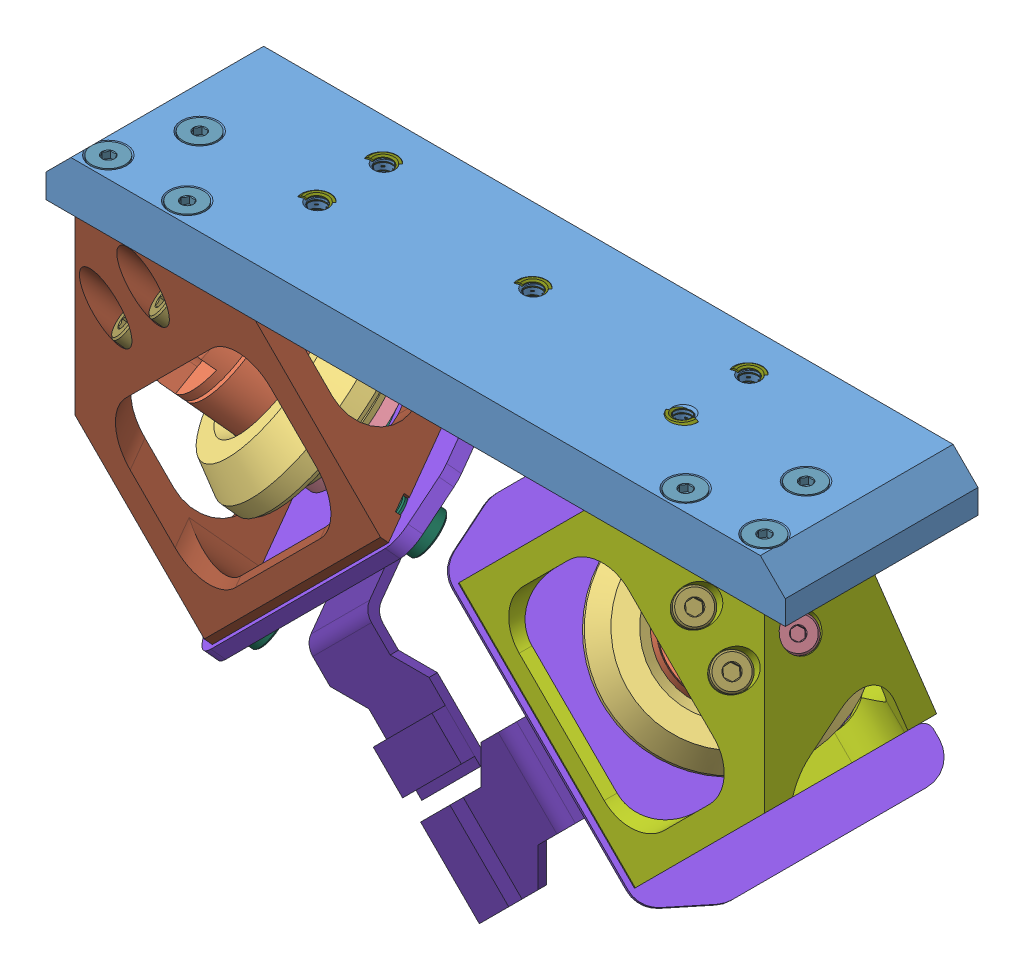
SolidWorks assembly MountingBracket, configuration Default. Lengths in mm.
Overall size (113.8 64.31 58.35).
58 component instances, 17 part files, 131 mates.
Components (placement in the parent):
- MountingBeamV2-2: MountingBeamV2 [Default] at (32.7849 42.1451 71.4667) size (89 6.09 23.2)
- ReactionWheelMotorUnit-1: ReactionWheelMotorUnit [Default] at (54.6479 30.2352 95.8648) x (-0.353553 -0.353553 0.866025) z (0.707107 -0.707107 0) size (41.14 45.44 40)
  - D1104-4000KV_rough-1: D1104-4000KV_rough [Default] at (-20.9844 2.2531 6.8074) size (14 17.5 19.2)
  - wheel-1: wheel [Default] at (-20.9844 14.7531 6.8074) x (0 0 -1) z (1 0 0) size (25 7.95 25)
  - magnetCap-1: magnetCap [Default] at (-20.9844 19.7531 6.8074) x (0 0 -1) z (-1 0 0) size (14.5 3.5 14.5)
  - magnet-1: magnet [Default] at (-20.9844 16.2531 6.8074) x (1 0 0) z (0 1 0) size (6 6 2.5)
  - sensorStandin-1: sensorStandin [Default] at (-20.9844 20.2031 6.8074) x (-1 0 0) z (0 0 -1) size (5 1.2 4.4)
  - motorBracketV2-1: motorBracketV2 [Default] at (-15.8154 -0.7969 -8.1926) x (0 0 1) z (-0.5 -0.866025 0) size (30 25.5 37.75)
  - encoderBoard-1: encoderBoard [shoulderScrews] at (-17.6931 21.4031 6.8074) x (0 0 -1) z (1 0 0) size (40 3.2 29.5)
  - 93395A137_TYPE 316 SS FLAT-HEAD SOCKET CAP SCREW-1: 93395A137_TYPE 316 SS FLAT-HEAD SOCKET CAP SCREW [93395A137] at (-20.9844 19.7531 2.0574) x (1 0 0) z (0 1 0) size (4 4 5.21)
  - 93395A137_TYPE 316 SS FLAT-HEAD SOCKET CAP SCREW-2: 93395A137_TYPE 316 SS FLAT-HEAD SOCKET CAP SCREW [93395A137] at (-20.9844 19.7531 11.5574) x (1 0 0) z (0 1 0) size (4 4 5.21)
  - 93395A138_REACTION WHEEL TYPE 316 SS FLAT-HEAD SOCKET CAP SCREW-1: 93395A138_REACTION WHEEL TYPE 316 SS FLAT-HEAD SOCKET CAP SCREW [93395A138] at (-19.2167 16.5531 8.5752) x (1 0 0) z (0 1 0) size (3.5 4 6.14)
  - 93395A138_REACTION WHEEL TYPE 316 SS FLAT-HEAD SOCKET CAP SCREW-3: 93395A138_REACTION WHEEL TYPE 316 SS FLAT-HEAD SOCKET CAP SCREW [93395A138] at (-22.7522 16.5531 8.5752) x (1 0 0) z (0 1 0) size (3.5 4 6.14)
  - 93395A138_REACTION WHEEL TYPE 316 SS FLAT-HEAD SOCKET CAP SCREW-4: 93395A138_REACTION WHEEL TYPE 316 SS FLAT-HEAD SOCKET CAP SCREW [93395A138] at (-22.7522 16.5531 5.0396) x (1 0 0) z (0 1 0) size (3.5 4 6.14)
  - 93395A138_REACTION WHEEL TYPE 316 SS FLAT-HEAD SOCKET CAP SCREW-5: 93395A138_REACTION WHEEL TYPE 316 SS FLAT-HEAD SOCKET CAP SCREW [93395A138] at (-19.2167 16.5531 5.0396) x (1 0 0) z (0 1 0) size (3.5 4 6.14)
- ReactionWheelMotorUnitReverse-1: ReactionWheelMotorUnitReverse [Default] at (-3.9163 45.0735 59.5186) x (-0.353553 0.353553 -0.866025) z (-0.707107 -0.707107 0) size (41.14 45.44 40)
  - D1104-4000KV_rough-1: D1104-4000KV_rough [Default] at (-20.9844 2.2531 6.8074) size (14 17.5 19.2)
  - wheel-1: wheel [Default] at (-20.9844 14.7531 6.8074) size (25 7.95 25)
  - magnetCap-1: magnetCap [Default] at (-20.9844 19.7531 6.8074) x (-1 0 0) z (0 0 1) size (14.5 3.5 14.5)
  - magnet-1: magnet [Default] at (-20.9844 16.2531 6.8074) x (1 0 0) z (0 1 0) size (6 6 2.5)
  - sensorStandin-1: sensorStandin [Default] at (-20.9844 20.2031 6.8074) x (0 0 -1) z (1 0 0) size (5 1.2 4.4)
  - motorBracketV2Reverse-1: motorBracketV2Reverse [Default] at (-26.1535 -0.7969 21.8074) x (0 0 -1) z (0.5 -0.866025 0) size (30 25.5 37.75)
  - encoderBoard-1: encoderBoard [shoulderScrews] at (-24.2758 21.4031 6.8074) x (0 0 1) z (-1 0 0) size (40 3.2 29.5)
  - 93395A137_TYPE 316 SS FLAT-HEAD SOCKET CAP SCREW-1: 93395A137_TYPE 316 SS FLAT-HEAD SOCKET CAP SCREW [93395A137] at (-16.2344 19.7531 6.8074) x (1 0 0) z (0 1 0) size (4 4 5.21)
  - 93395A137_TYPE 316 SS FLAT-HEAD SOCKET CAP SCREW-2: 93395A137_TYPE 316 SS FLAT-HEAD SOCKET CAP SCREW [93395A137] at (-25.7344 19.7531 6.8074) x (1 0 0) z (0 1 0) size (4 4 5.21)
  - 93395A138_REACTION WHEEL TYPE 316 SS FLAT-HEAD SOCKET CAP SCREW-1: 93395A138_REACTION WHEEL TYPE 316 SS FLAT-HEAD SOCKET CAP SCREW [93395A138] at (-22.7522 16.5531 8.5752) x (1 0 0) z (0 1 0) size (3.5 4 6.14)
  - 93395A138_REACTION WHEEL TYPE 316 SS FLAT-HEAD SOCKET CAP SCREW-2: 93395A138_REACTION WHEEL TYPE 316 SS FLAT-HEAD SOCKET CAP SCREW [93395A138] at (-19.2167 16.5531 8.5752) x (1 0 0) z (0 1 0) size (3.5 4 6.14)
  - 93395A138_REACTION WHEEL TYPE 316 SS FLAT-HEAD SOCKET CAP SCREW-3: 93395A138_REACTION WHEEL TYPE 316 SS FLAT-HEAD SOCKET CAP SCREW [93395A138] at (-19.2167 16.5531 5.0396) x (1 0 0) z (0 1 0) size (3.5 4 6.14)
  - 93395A138_REACTION WHEEL TYPE 316 SS FLAT-HEAD SOCKET CAP SCREW-4: 93395A138_REACTION WHEEL TYPE 316 SS FLAT-HEAD SOCKET CAP SCREW [93395A138] at (-22.7522 16.5531 5.0396) x (1 0 0) z (0 1 0) size (3.5 4 6.14)
- 92290A012_TYPE 316 SS SOCKET HEAD CAP SCREW-6: 92290A012_TYPE 316 SS SOCKET HEAD CAP SCREW [92290A012] at (0.4749 26.5551 78.0709) x (0.72702 0.684653 0.051888) z (0.612372 -0.612372 -0.5) size (3.8 3.8 7.44)
- 92290A012_TYPE 316 SS SOCKET HEAD CAP SCREW-9: 92290A012_TYPE 316 SS SOCKET HEAD CAP SCREW [92290A012] at (60.595 31.0551 78.0709) x (0.72702 -0.684653 -0.051888) z (-0.612372 -0.612372 -0.5) size (3.8 3.8 7.44)
- 92290A012_TYPE 316 SS SOCKET HEAD CAP SCREW-7: 92290A012_TYPE 316 SS SOCKET HEAD CAP SCREW [92290A012] at (65.095 26.5551 78.0709) x (0.72702 -0.684653 -0.051888) z (-0.612372 -0.612372 -0.5) size (3.8 3.8 7.44)
- 92290A012_TYPE 316 SS SOCKET HEAD CAP SCREW-8: 92290A012_TYPE 316 SS SOCKET HEAD CAP SCREW [92290A012] at (4.9749 31.0551 78.0709) x (0.094564 0.684653 -0.722709) z (0.612372 -0.612372 -0.5) size (3.8 3.8 7.44)
- 92855A839_18-8 SS LOW-PROFILE SCKT HEAD SCREWS-7: 92855A839_18-8 SS LOW-PROFILE SCKT HEAD SCREWS [92855A839] at (67.0388 28.4989 72.3095) x (-0.632456 0 0.774597) z (-0.612372 -0.612372 -0.5) size (3.8 3.8 9.77)
- 92855A839_18-8 SS LOW-PROFILE SCKT HEAD SCREWS-5: 92855A839_18-8 SS LOW-PROFILE SCKT HEAD SCREWS [92855A839] at (-1.4689 28.4989 72.3095) x (0.632456 0 0.774597) z (0.612372 -0.612372 -0.5) size (3.8 3.8 9.77)
- 92855A839_18-8 SS LOW-PROFILE SCKT HEAD SCREWS-4: 92855A839_18-8 SS LOW-PROFILE SCKT HEAD SCREWS [92855A839] at (62.5388 32.9989 72.3095) x (-0.047367 0.65974 -0.75) z (-0.612372 -0.612372 -0.5) size (3.8 3.8 9.77)
- 92855A839_18-8 SS LOW-PROFILE SCKT HEAD SCREWS-6: 92855A839_18-8 SS LOW-PROFILE SCKT HEAD SCREWS [92855A839] at (3.0311 32.9989 72.3095) x (0.707107 0.707107 0) z (0.612372 -0.612372 -0.5) size (3.8 3.8 9.77)
- 93395A138_TYPE 316 SS FLAT-HEAD SOCKET CAP SCREW-7: 93395A138_TYPE 316 SS FLAT-HEAD SOCKET CAP SCREW [93395A138] at (72.2849 46.1451 80.5667) x (-0.866025 0 -0.5) z (0 1 0) size (4 4 6.22)
- 93395A138_TYPE 316 SS FLAT-HEAD SOCKET CAP SCREW-6: 93395A138_TYPE 316 SS FLAT-HEAD SOCKET CAP SCREW [93395A138] at (62.7849 46.1451 80.5667) x (0.866025 0 -0.5) z (0 1 0) size (4 4 6.22)
- 93395A138_TYPE 316 SS FLAT-HEAD SOCKET CAP SCREW-5: 93395A138_TYPE 316 SS FLAT-HEAD SOCKET CAP SCREW [93395A138] at (-3.7151 46.1451 72.5667) x (0 0 -1) z (0 1 0) size (4 4 6.22)
- 93395A138_TYPE 316 SS FLAT-HEAD SOCKET CAP SCREW-4: 93395A138_TYPE 316 SS FLAT-HEAD SOCKET CAP SCREW [93395A138] at (2.7849 46.1451 80.5667) x (0 0 1) z (0 1 0) size (4 4 6.22)
- 93395A138_TYPE 316 SS FLAT-HEAD SOCKET CAP SCREW-8: 93395A138_TYPE 316 SS FLAT-HEAD SOCKET CAP SCREW [93395A138] at (69.2849 46.1451 72.5667) x (0.866025 0 -0.5) z (0 1 0) size (4 4 6.22)
- 93395A138_TYPE 316 SS FLAT-HEAD SOCKET CAP SCREW-9: 93395A138_TYPE 316 SS FLAT-HEAD SOCKET CAP SCREW [93395A138] at (-6.7151 46.1451 80.5667) x (0 0 1) z (0 1 0) size (4 4 6.22)
- 92290A012_TYPE 316 SS SOCKET HEAD CAP SCREW-13: 92290A012_TYPE 316 SS SOCKET HEAD CAP SCREW [92290A012] at (15.9156 34.7063 60.4988) x (-0.419788 -0.7878 0.45072) z (-0.612372 0.612372 0.5) size (3.8 3.8 7.44)
- 92290A012_TYPE 316 SS SOCKET HEAD CAP SCREW-12: 92290A012_TYPE 316 SS SOCKET HEAD CAP SCREW [92290A012] at (49.6542 34.7063 60.4988) x (0.771612 -0.325295 -0.546625) z (0.612372 0.612372 0.5) size (3.8 3.8 7.44)
- 92290A012_TYPE 316 SS SOCKET HEAD CAP SCREW-11: 92290A012_TYPE 316 SS SOCKET HEAD CAP SCREW [92290A012] at (68.7461 15.6144 60.4988) x (-0.742298 0.662993 0.097129) z (0.612372 0.612372 0.5) size (3.8 3.8 7.44)
- 92290A012_TYPE 316 SS SOCKET HEAD CAP SCREW-10: 92290A012_TYPE 316 SS SOCKET HEAD CAP SCREW [92290A012] at (-3.1762 15.6144 60.4988) x (0.773051 0.331426 0.540878) z (-0.612372 0.612372 0.5) size (3.8 3.8 7.44)
- M2x0.4x6mm_shoulderScrew_90278A431_18-8 STAINLESS STEEL PRECISION SHOULDER SCREW-1: M2x0.4x6mm_shoulderScrew_90278A431_18-8 STAINLESS STEEL PRECISION SHOULDER SCREW [90278A431] at (56.3278 3.196 76.9174) x (-0.615543 0.766199 -0.184515) z (-0.612372 -0.612372 -0.5) size (5 5 8.25)
- M2x0.4x6mm_shoulderScrew_90278A431_18-8 STAINLESS STEEL PRECISION SHOULDER SCREW-2: M2x0.4x6mm_shoulderScrew_90278A431_18-8 STAINLESS STEEL PRECISION SHOULDER SCREW [90278A431] at (37.2359 22.2879 76.9174) x (-0.673365 0.735396 -0.075972) z (-0.612372 -0.612372 -0.5) size (5 5 8.25)
- M2x0.4x6mm_shoulderScrew_90278A431_18-8 STAINLESS STEEL PRECISION SHOULDER SCREW-3: M2x0.4x6mm_shoulderScrew_90278A431_18-8 STAINLESS STEEL PRECISION SHOULDER SCREW [90278A431] at (9.2421 3.196 76.9174) x (-0.615543 0.027548 -0.787622) z (0.612372 -0.612372 -0.5) size (5 5 8.25)
- M2x0.4x6mm_shoulderScrew_90278A431_18-8 STAINLESS STEEL PRECISION SHOULDER SCREW-4: M2x0.4x6mm_shoulderScrew_90278A431_18-8 STAINLESS STEEL PRECISION SHOULDER SCREW [90278A431] at (28.334 22.2879 76.9174) x (-0.482367 -0.790505 0.37739) z (0.612372 -0.612372 -0.5) size (5 5 8.25)
- 91630A221_SCREW-LOCK HELICAL INSERTS WITHOUT PRONG-1: 91630A221_SCREW-LOCK HELICAL INSERTS WITHOUT PRONG [91630A221] at (54.7849 46.1451 72.8667) x (1 0 0) z (0 0 -1) size (3.78 2.46 4.27)
- 91630A221_SCREW-LOCK HELICAL INSERTS WITHOUT PRONG-2: 91630A221_SCREW-LOCK HELICAL INSERTS WITHOUT PRONG [91630A221] at (54.7849 46.1451 64.8667) x (-0.939694 0 0.342017) z (0.342017 0 0.939694) size (3.78 2.46 4.27)
- 91630A221_SCREW-LOCK HELICAL INSERTS WITHOUT PRONG-3: 91630A221_SCREW-LOCK HELICAL INSERTS WITHOUT PRONG [91630A221] at (32.7849 46.1451 68.8667) x (-0.939694 0 0.342017) z (0.342017 0 0.939694) size (3.78 2.46 4.27)
- 91630A221_SCREW-LOCK HELICAL INSERTS WITHOUT PRONG-4: 91630A221_SCREW-LOCK HELICAL INSERTS WITHOUT PRONG [91630A221] at (10.7849 46.1451 64.8667) x (-0.939694 0 0.342017) z (0.342017 0 0.939694) size (3.78 2.46 4.27)
- 91630A221_SCREW-LOCK HELICAL INSERTS WITHOUT PRONG-5: 91630A221_SCREW-LOCK HELICAL INSERTS WITHOUT PRONG [91630A221] at (10.7849 46.1451 72.8667) x (-0.939694 0 0.342017) z (0.342017 0 0.939694) size (3.78 2.46 4.27)
- encoderCable-1: encoderCable [Default] at (52.5468 2.9364 82.6661) x (-0.707107 0.707107 0) z (-0.707107 -0.707107 0) size (13.31 11.37 21.76)
- encoderCable-2: encoderCable [Default] at (28.5936 18.5069 82.6661) x (-0.707107 -0.707107 0) z (0.707107 -0.707107 0) size (13.31 11.37 21.76)
Mates (geometry in assembly coordinates):
- Concentric1: concentric aligned: cylinder of MountingBeamV2-2 through (2.7849 46.1451 80.5667) axis (0 1 0) radius 1.2; cylinder of ReactionWheelMotorUnitReverse-1/motorBracketV2Reverse-1 through (2.7849 40.2451 80.5667) axis (0 1 0) radius 0.8
- Concentric2: concentric aligned: cylinder of MountingBeamV2-2 through (-6.7151 46.1451 80.5667) axis (0 1 0) radius 1.2; cylinder of ReactionWheelMotorUnitReverse-1/motorBracketV2Reverse-1 through (-6.7151 40.2451 80.5667) axis (0 1 0) radius 0.8
- Coincident1: coincident anti-aligned: plane of MountingBeamV2-2 through (32.7849 40.2451 71.4667) normal (0 -1 0); plane of ReactionWheelMotorUnitReverse-1/motorBracketV2Reverse-1 through (12.4981 40.2451 57.0667) normal (0 1 0)
- Concentric3: concentric aligned: cylinder of MountingBeamV2-2 through (72.2849 46.1451 80.5667) axis (0 1 0) radius 1.2; cylinder of ReactionWheelMotorUnit-1/motorBracketV2-1 through (72.2849 40.2451 80.5667) axis (0 1 0) radius 0.8
- Concentric4: concentric aligned: cylinder of MountingBeamV2-2 through (62.7849 46.1451 80.5667) axis (0 1 0) radius 1.2; cylinder of ReactionWheelMotorUnit-1/motorBracketV2-1 through (62.7849 40.2451 80.5667) axis (0 1 0) radius 0.8
- Coincident2: coincident anti-aligned: plane of MountingBeamV2-2 through (32.7849 40.2451 71.4667) normal (0 -1 0); plane of ReactionWheelMotorUnit-1/motorBracketV2-1 through (74.2849 40.2451 57.0667) normal (0 1 0)
- Concentric6: concentric anti-aligned: cylinder of ReactionWheelMotorUnit-1/encoderBoard-1 through (46.5924 31.6444 57.9988) axis (-0.612372 -0.612372 -0.5) radius 1.5; cylinder of 90318A101_ULTRA-LOW-PROFILE PRECISION SHOULDER SCREW-1 through (50.4809 35.533 61.1738) axis (0.612372 0.612372 0.5) radius 1.1906
- Coincident3: coincident anti-aligned: plane of ReactionWheelMotorUnit-1/encoderBoard-1 through (51.6305 17.5906 69.0406) normal (-0.612372 -0.612372 -0.5); plane of 90318A101_ULTRA-LOW-PROFILE PRECISION SHOULDER SCREW-1 through (44.9086 33.3282 57.9988) normal (0.612372 0.612372 0.5)
- Concentric12: concentric anti-aligned: cylinder of ReactionWheelMotorUnitReverse-1/motorBracketV2Reverse-1 through (2.4081 24.622 76.4924) axis (-0.612372 0.612372 0.5) radius 2; cylinder of 92290A012_TYPE 316 SS SOCKET HEAD CAP SCREW-6 through (-3.8117 30.8417 81.5709) axis (0.612372 -0.612372 -0.5) radius 1.9
- Coincident9: coincident anti-aligned: plane of ReactionWheelMotorUnitReverse-1/motorBracketV2Reverse-1 through (-10.241 20.5578 82.2917) normal (-0.612372 0.612372 0.5); plane of 92290A012_TYPE 316 SS SOCKET HEAD CAP SCREW-6 through (-2.587 29.617 80.5709) normal (0.612372 -0.612372 -0.5)
- Concentric13: concentric anti-aligned: cylinder of ReactionWheelMotorUnitReverse-1/motorBracketV2Reverse-1 through (6.9081 29.122 76.4924) axis (-0.612372 0.612372 0.5) radius 2; cylinder of 92290A012_TYPE 316 SS SOCKET HEAD CAP SCREW-8 through (0.6883 35.3417 81.5709) axis (0.612372 -0.612372 -0.5) radius 1.9
- Coincident11: coincident anti-aligned: plane of ReactionWheelMotorUnitReverse-1/motorBracketV2Reverse-1 through (-10.241 20.5578 82.2917) normal (-0.612372 0.612372 0.5); plane of 92290A012_TYPE 316 SS SOCKET HEAD CAP SCREW-8 through (1.913 34.117 80.5709) normal (0.612372 -0.612372 -0.5)
- Concentric14: concentric anti-aligned: cylinder of ReactionWheelMotorUnit-1/motorBracketV2-1 through (58.6618 29.122 76.4924) axis (0.612372 0.612372 0.5) radius 2; cylinder of 92290A012_TYPE 316 SS SOCKET HEAD CAP SCREW-9 through (64.8816 35.3417 81.5709) axis (-0.612372 -0.612372 -0.5) radius 1.9
- Concentric15: concentric anti-aligned: cylinder of ReactionWheelMotorUnit-1/motorBracketV2-1 through (63.1618 24.622 76.4924) axis (0.612372 0.612372 0.5) radius 2; cylinder of 92290A012_TYPE 316 SS SOCKET HEAD CAP SCREW-7 through (69.3816 30.8417 81.5709) axis (-0.612372 -0.612372 -0.5) radius 1.9
- Coincident12: coincident anti-aligned: plane of ReactionWheelMotorUnit-1/motorBracketV2-1 through (54.5977 41.771 82.2917) normal (0.612372 0.612372 0.5); plane of 92290A012_TYPE 316 SS SOCKET HEAD CAP SCREW-7 through (68.1568 29.617 80.5709) normal (-0.612372 -0.612372 -0.5)
- Coincident13: coincident anti-aligned: plane of ReactionWheelMotorUnit-1/motorBracketV2-1 through (54.5977 41.771 82.2917) normal (0.612372 0.612372 0.5); plane of 92290A012_TYPE 316 SS SOCKET HEAD CAP SCREW-9 through (63.6568 34.117 80.5709) normal (-0.612372 -0.612372 -0.5)
- Coincident24: coincident aligned: cone of MountingBeamV2-2 through (62.7849 46.1451 80.5667) axis (0 -1 0); cone of 93395A138_TYPE 316 SS FLAT-HEAD SOCKET CAP SCREW-6 through (62.7849 44.9451 80.5667) axis (0 -1 0)
- Coincident25: coincident aligned: cone of MountingBeamV2-2 through (72.2849 46.1451 80.5667) axis (0 -1 0); cone of 93395A138_TYPE 316 SS FLAT-HEAD SOCKET CAP SCREW-7 through (72.2849 44.9451 80.5667) axis (0 -1 0)
- Coincident26: coincident aligned: cone of MountingBeamV2-2 through (69.2849 46.1451 72.5667) axis (0 -1 0); cone of 93395A138_TYPE 316 SS FLAT-HEAD SOCKET CAP SCREW-8 through (69.2849 44.9451 72.5667) axis (0 -1 0)
- Coincident28: coincident aligned: cone of MountingBeamV2-2 through (-6.7151 46.1451 80.5667) axis (0 -1 0); cone of 93395A138_TYPE 316 SS FLAT-HEAD SOCKET CAP SCREW-9 through (-6.7151 44.9451 80.5667) axis (0 -1 0)
- Coincident29: coincident aligned: cone of MountingBeamV2-2 through (2.7849 46.1451 80.5667) axis (0 -1 0); cone of 93395A138_TYPE 316 SS FLAT-HEAD SOCKET CAP SCREW-4 through (2.7849 44.9451 80.5667) axis (0 -1 0)
- Coincident30: coincident aligned: cone of MountingBeamV2-2 through (-3.7151 46.1451 72.5667) axis (0 -1 0); cone of 93395A138_TYPE 316 SS FLAT-HEAD SOCKET CAP SCREW-5 through (-3.7151 44.9451 72.5667) axis (0 -1 0)
- Concentric20: concentric anti-aligned: cylinder of ReactionWheelMotorUnit-1/motorBracketV2-1 through (66.664 13.5323 58.7988) axis (-0.612372 -0.612372 -0.5) radius 1; cylinder of 90318A101_ULTRA-LOW-PROFILE PRECISION SHOULDER SCREW-2 through (69.5728 16.4411 61.1738) axis (0.612372 0.612372 0.5) radius 1.1906
- Concentric21: concentric anti-aligned: cylinder of ReactionWheelMotorUnit-1/motorBracketV2-1 through (39.4404 24.4925 78.7174) axis (-0.612372 -0.612372 -0.5) radius 1; cylinder of 90318A101_ULTRA-LOW-PROFILE PRECISION SHOULDER SCREW-3 through (42.3492 27.4012 81.0924) axis (0.612372 0.612372 0.5) radius 1.1906
- Concentric22: concentric anti-aligned: circle of ReactionWheelMotorUnit-1/motorBracketV2-1; cylinder of 90318A101_ULTRA-LOW-PROFILE PRECISION SHOULDER SCREW-8 through (61.4411 8.3093 81.0924) axis (0.612372 0.612372 0.5) radius 1.1906
- Concentric23: concentric anti-aligned: cylinder of ReactionWheelMotorUnitReverse-1/motorBracketV2Reverse-1 through (17.9977 32.6242 58.7988) axis (0.612372 -0.612372 -0.5) radius 1; cylinder of 90318A101_ULTRA-LOW-PROFILE PRECISION SHOULDER SCREW-5 through (15.0889 35.533 61.1738) axis (-0.612372 0.612372 0.5) radius 1.1906
- Concentric24: concentric anti-aligned: cylinder of ReactionWheelMotorUnitReverse-1/motorBracketV2Reverse-1 through (-1.0942 13.5323 58.7988) axis (0.612372 -0.612372 -0.5) radius 1; cylinder of 90318A101_ULTRA-LOW-PROFILE PRECISION SHOULDER SCREW-4 through (-4.0029 16.4411 61.1738) axis (-0.612372 0.612372 0.5) radius 1.1906
- Concentric25: concentric anti-aligned: cylinder of ReactionWheelMotorUnitReverse-1/motorBracketV2Reverse-1 through (7.0375 5.4006 78.7174) axis (0.612372 -0.612372 -0.5) radius 1; cylinder of 90318A101_ULTRA-LOW-PROFILE PRECISION SHOULDER SCREW-6 through (4.1288 8.3093 81.0924) axis (-0.612372 0.612372 0.5) radius 1.1906
- Concentric26: concentric anti-aligned: cylinder of ReactionWheelMotorUnitReverse-1/motorBracketV2Reverse-1 through (26.1294 24.4925 78.7174) axis (0.612372 -0.612372 -0.5) radius 1; cylinder of 90318A101_ULTRA-LOW-PROFILE PRECISION SHOULDER SCREW-7 through (23.2207 27.4012 81.0924) axis (-0.612372 0.612372 0.5) radius 1.1906
- Coincident31: coincident anti-aligned: plane of ReactionWheelMotorUnitReverse-1/encoderBoard-1 through (13.9394 17.5906 69.0406) normal (0.612372 -0.612372 -0.5); plane of 90318A101_ULTRA-LOW-PROFILE PRECISION SHOULDER SCREW-4 through (0.9229 14.4317 56.9677) normal (-0.612372 0.612372 0.5)
- Coincident32: coincident anti-aligned: plane of ReactionWheelMotorUnitReverse-1/encoderBoard-1 through (13.9394 17.5906 69.0406) normal (0.612372 -0.612372 -0.5); plane of 90318A101_ULTRA-LOW-PROFILE PRECISION SHOULDER SCREW-6 through (6.3335 2.737 77.9174) normal (-0.612372 0.612372 0.5)
- Coincident33: coincident anti-aligned: plane of ReactionWheelMotorUnitReverse-1/encoderBoard-1 through (13.9394 17.5906 69.0406) normal (0.612372 -0.612372 -0.5); plane of 90318A101_ULTRA-LOW-PROFILE PRECISION SHOULDER SCREW-7 through (27.222 25.0837 76.1314) normal (-0.612372 0.612372 0.5)
- Coincident34: coincident anti-aligned: plane of ReactionWheelMotorUnitReverse-1/encoderBoard-1 through (13.9394 17.5906 69.0406) normal (0.612372 -0.612372 -0.5); plane of 90318A101_ULTRA-LOW-PROFILE PRECISION SHOULDER SCREW-5 through (20.0148 33.5236 56.9677) normal (-0.612372 0.612372 0.5)
- Coincident35: coincident anti-aligned: plane of ReactionWheelMotorUnit-1/encoderBoard-1 through (51.6305 17.5906 69.0406) normal (-0.612372 -0.612372 -0.5); plane of 90318A101_ULTRA-LOW-PROFILE PRECISION SHOULDER SCREW-3 through (38.3478 25.0837 76.1314) normal (0.612372 0.612372 0.5)
- Coincident36: coincident anti-aligned: plane of ReactionWheelMotorUnit-1/encoderBoard-1 through (51.6305 17.5906 69.0406) normal (-0.612372 -0.612372 -0.5); plane of 90318A101_ULTRA-LOW-PROFILE PRECISION SHOULDER SCREW-8 through (57.4397 5.9918 76.1314) normal (0.612372 0.612372 0.5)
- Coincident37: coincident anti-aligned: plane of ReactionWheelMotorUnit-1/encoderBoard-1 through (51.6305 17.5906 69.0406) normal (-0.612372 -0.612372 -0.5); plane of 90318A101_ULTRA-LOW-PROFILE PRECISION SHOULDER SCREW-2 through (65.5714 14.1235 56.2129) normal (0.612372 0.612372 0.5)
- Coincident38: coincident anti-aligned: plane of MountingBeamV2-2 through (32.7849 46.1451 71.4667) normal (0 1 0); plane of 91630A221_SCREW-LOCK HELICAL INSERTS WITHOUT PRONG-1 through (54.7849 46.1451 72.8667) normal (0 -1 0)
- Coincident39: coincident: line of MountingBeamV2-2 through (54.7849 40.2451 72.8667) axis (0 1 0); unknown of 91630A221_SCREW-LOCK HELICAL INSERTS WITHOUT PRONG-1
- Parallel1: parallel anti-aligned: plane of MountingBeamV2-2 through (77.2849 40.2451 83.0667) normal (0 0 1); plane of 91630A221_SCREW-LOCK HELICAL INSERTS WITHOUT PRONG-1 through (55.7914 46.1451 72.8667) normal (0 0 -1)
- Coincident41: coincident anti-aligned: plane of MountingBeamV2-2 through (32.7849 46.1451 71.4667) normal (0 1 0); plane of 91630A221_SCREW-LOCK HELICAL INSERTS WITHOUT PRONG-2 through (54.7849 46.1451 64.8667) normal (0 -1 0)
- Parallel2: parallel aligned: plane of MountingBeamV2-2 through (77.2849 40.2451 83.0667) normal (0 0 1); plane of 91630A221_SCREW-LOCK HELICAL INSERTS WITHOUT PRONG-2 through (55.7914 44.1237 64.8668) normal (0 0 1)
- Coincident43: coincident: line of MountingBeamV2-2 through (54.7849 40.2451 64.8667) axis (0 1 0); unknown of 91630A221_SCREW-LOCK HELICAL INSERTS WITHOUT PRONG-2
- Coincident46: coincident: line of MountingBeamV2-2 through (32.7849 40.2451 68.8667) axis (0 1 0); unknown of 91630A221_SCREW-LOCK HELICAL INSERTS WITHOUT PRONG-3
- Coincident47: coincident anti-aligned: plane of MountingBeamV2-2 through (32.7849 46.1451 71.4667) normal (0 1 0); plane of 91630A221_SCREW-LOCK HELICAL INSERTS WITHOUT PRONG-3 through (32.7849 46.1451 68.8667) normal (0 -1 0)
- Parallel3: parallel aligned: plane of MountingBeamV2-2 through (77.2849 40.2451 83.0667) normal (0 0 1); plane of 91630A221_SCREW-LOCK HELICAL INSERTS WITHOUT PRONG-3 through (33.7914 44.1237 68.8668) normal (0 0 1)
- Coincident51: coincident anti-aligned: plane of MountingBeamV2-2 through (32.7849 46.1451 71.4667) normal (0 1 0); plane of 91630A221_SCREW-LOCK HELICAL INSERTS WITHOUT PRONG-4 through (10.7849 46.1451 64.8667) normal (0 -1 0)
- Coincident52: coincident: line of MountingBeamV2-2 through (10.7849 40.2451 64.8667) axis (0 1 0); unknown of 91630A221_SCREW-LOCK HELICAL INSERTS WITHOUT PRONG-4
- Parallel4: parallel aligned: plane of MountingBeamV2-2 through (77.2849 40.2451 83.0667) normal (0 0 1); plane of 91630A221_SCREW-LOCK HELICAL INSERTS WITHOUT PRONG-4 through (11.7914 44.1237 64.8668) normal (0 0 1)
- Coincident54: coincident anti-aligned: plane of MountingBeamV2-2 through (32.7849 46.1451 71.4667) normal (0 1 0); plane of 91630A221_SCREW-LOCK HELICAL INSERTS WITHOUT PRONG-5 through (10.7849 46.1451 72.8667) normal (0 -1 0)
- Coincident55: coincident: line of MountingBeamV2-2 through (10.7849 40.2451 72.8667) axis (0 1 0); unknown of 91630A221_SCREW-LOCK HELICAL INSERTS WITHOUT PRONG-5
- Parallel5: parallel aligned: plane of MountingBeamV2-2 through (77.2849 40.2451 83.0667) normal (0 0 1); plane of 91630A221_SCREW-LOCK HELICAL INSERTS WITHOUT PRONG-5 through (11.7914 44.1237 72.8668) normal (0 0 1)
- Parallel6: parallel aligned: plane of MountingBeamV2-2 through (77.2849 40.2451 83.0667) normal (0 0 1); plane of 93395A138_TYPE 316 SS FLAT-HEAD SOCKET CAP SCREW-7 through (72.6602 45.3051 79.9167) normal (0 0 1)
- Parallel7: parallel aligned: plane of MountingBeamV2-2 through (77.2849 40.2451 83.0667) normal (0 0 1); plane of 93395A138_TYPE 316 SS FLAT-HEAD SOCKET CAP SCREW-6 through (63.1602 45.3051 79.9167) normal (0 0 1)
- Parallel8: parallel aligned: plane of MountingBeamV2-2 through (77.2849 40.2451 83.0667) normal (0 0 1); plane of 93395A138_TYPE 316 SS FLAT-HEAD SOCKET CAP SCREW-8 through (69.6602 45.3051 71.9167) normal (0 0 1)
- Parallel9: parallel aligned: plane of MountingBeamV2-2 through (77.2849 40.2451 83.0667) normal (0 0 1); plane of 93395A138_TYPE 316 SS FLAT-HEAD SOCKET CAP SCREW-4 through (3.1602 45.3051 79.9167) normal (0 0 1)
- Parallel10: parallel aligned: plane of MountingBeamV2-2 through (77.2849 40.2451 83.0667) normal (0 0 1); plane of 93395A138_TYPE 316 SS FLAT-HEAD SOCKET CAP SCREW-9 through (-6.3398 45.3051 79.9167) normal (0 0 1)
- Parallel11: parallel aligned: plane of MountingBeamV2-2 through (77.2849 40.2451 83.0667) normal (0 0 1); plane of 93395A138_TYPE 316 SS FLAT-HEAD SOCKET CAP SCREW-5 through (-3.3398 45.3051 71.9167) normal (0 0 1)
- Parallel12: parallel: line of ReactionWheelMotorUnitReverse-1/motorBracketV2Reverse-1 through (-8.7151 40.2451 82.5667) axis (0 -1 0); plane of 92290A012_TYPE 316 SS SOCKET HEAD CAP SCREW-6 through (-3.3918 30.4951 80.2597) normal (0.632456 0 0.774597)
- Parallel13: parallel: line of ReactionWheelMotorUnitReverse-1/motorBracketV2Reverse-1 through (-8.7151 40.2451 82.5667) axis (0 -1 0); plane of 92290A012_TYPE 316 SS SOCKET HEAD CAP SCREW-8 through (1.1082 34.9951 80.2597) normal (0.632456 0 0.774597)
- Parallel15: parallel: line of ReactionWheelMotorUnit-1/motorBracketV2-1 through (74.2849 19.0319 82.5667) axis (0 1 0); plane of 92290A012_TYPE 316 SS SOCKET HEAD CAP SCREW-9 through (63.5129 34.9951 81.4216) normal (0.632456 0 -0.774597)
- Parallel16: parallel: line of ReactionWheelMotorUnit-1/motorBracketV2-1 through (74.2849 19.0319 82.5667) axis (0 1 0); plane of 92290A012_TYPE 316 SS SOCKET HEAD CAP SCREW-7 through (69.3724 29.8105 80.5951) normal (-0.632456 0 0.774597)
- Parallel18: parallel aligned: plane of ReactionWheelMotorUnit-1/encoderBoard-1 through (60.5577 -1.7664 81.8145) normal (-0.353553 -0.353553 0.866025); plane of 90318A101_ULTRA-LOW-PROFILE PRECISION SHOULDER SCREW-8 through (57.2661 4.7824 77.0315) normal (-0.353553 -0.353553 0.866025)
- Parallel19: parallel aligned: plane of ReactionWheelMotorUnit-1/encoderBoard-1 through (60.5577 -1.7664 81.8145) normal (-0.353553 -0.353553 0.866025); plane of 90318A101_ULTRA-LOW-PROFILE PRECISION SHOULDER SCREW-2 through (65.3978 12.9142 57.1129) normal (-0.353553 -0.353553 0.866025)
- Parallel20: parallel aligned: plane of ReactionWheelMotorUnit-1/encoderBoard-1 through (60.5577 -1.7664 81.8145) normal (-0.353553 -0.353553 0.866025); plane of 90318A101_ULTRA-LOW-PROFILE PRECISION SHOULDER SCREW-3 through (38.1742 23.8743 77.0315) normal (-0.353553 -0.353553 0.866025)
- Parallel21: parallel aligned: plane of ReactionWheelMotorUnit-1/encoderBoard-1 through (60.5577 -1.7664 81.8145) normal (-0.353553 -0.353553 0.866025); plane of 90318A101_ULTRA-LOW-PROFILE PRECISION SHOULDER SCREW-1 through (46.3059 32.006 57.1129) normal (-0.353553 -0.353553 0.866025)
- Parallel22: parallel aligned: plane of ReactionWheelMotorUnitReverse-1/encoderBoard-1 through (33.2964 26.5179 81.8145) normal (0.353553 -0.353553 0.866025); plane of 90318A101_ULTRA-LOW-PROFILE PRECISION SHOULDER SCREW-6 through (7.6557 4.1343 77.0315) normal (0.353553 -0.353553 0.866025)
- Parallel23: parallel aligned: plane of ReactionWheelMotorUnitReverse-1/encoderBoard-1 through (33.2964 26.5179 81.8145) normal (0.353553 -0.353553 0.866025); plane of 90318A101_ULTRA-LOW-PROFILE PRECISION SHOULDER SCREW-7 through (26.7476 23.2262 77.0315) normal (0.353553 -0.353553 0.866025)
- Parallel24: parallel aligned: plane of ReactionWheelMotorUnitReverse-1/encoderBoard-1 through (-5.4177 8.6634 56.2667) normal (-0.707107 -0.707107 0); plane of 90318A101_ULTRA-LOW-PROFILE PRECISION SHOULDER SCREW-4 through (0.5279 13.0328 57.4035) normal (-0.707107 -0.707107 0)
- Parallel25: parallel aligned: plane of ReactionWheelMotorUnitReverse-1/encoderBoard-1 through (-5.4177 8.6634 56.2667) normal (-0.707107 -0.707107 0); plane of 90318A101_ULTRA-LOW-PROFILE PRECISION SHOULDER SCREW-5 through (19.6198 32.1246 57.4035) normal (-0.707107 -0.707107 0)
- Coincident56: coincident anti-aligned: plane of ReactionWheelMotorUnitReverse-1/motorBracketV2Reverse-1 through (-11.772 22.0888 83.5417) normal (-0.612372 0.612372 0.5); plane of 92855A839_18-8 SS LOW-PROFILE SCKT HEAD SCREWS-5 through (-6.3679 33.3979 76.3095) normal (0.612372 -0.612372 -0.5)
- Concentric27: concentric anti-aligned: circle of ReactionWheelMotorUnitReverse-1/motorBracketV2Reverse-1; circle of 92855A839_18-8 SS LOW-PROFILE SCKT HEAD SCREWS-5
- Parallel26: parallel: line of ReactionWheelMotorUnitReverse-1/motorBracketV2Reverse-1 through (-8.7151 40.2451 82.5667) axis (0 -1 0); plane of 92855A839_18-8 SS LOW-PROFILE SCKT HEAD SCREWS-5 through (-6.8306 33.9242 75.8482) normal (0.632456 0 0.774597)
- Coincident57: coincident anti-aligned: plane of ReactionWheelMotorUnit-1/motorBracketV2-1 through (56.1286 43.302 83.5417) normal (0.612372 0.612372 0.5); plane of 92855A839_18-8 SS LOW-PROFILE SCKT HEAD SCREWS-7 through (71.9378 33.3979 76.3095) normal (-0.612372 -0.612372 -0.5)
- Concentric28: concentric aligned: circle of ReactionWheelMotorUnit-1/motorBracketV2-1; circle of 92855A839_18-8 SS LOW-PROFILE SCKT HEAD SCREWS-7
- Parallel27: parallel: line of ReactionWheelMotorUnit-1/motorBracketV2-1 through (74.2849 19.0319 82.5667) axis (0 1 0); plane of 92855A839_18-8 SS LOW-PROFILE SCKT HEAD SCREWS-7 through (71.5783 33.9242 76.8551) normal (0.632456 0 -0.774597)
- Concentric29: concentric aligned: circle of ReactionWheelMotorUnitReverse-1/motorBracketV2Reverse-1; circle of 92855A839_18-8 SS LOW-PROFILE SCKT HEAD SCREWS-6
- Coincident58: coincident anti-aligned: plane of ReactionWheelMotorUnitReverse-1/motorBracketV2Reverse-1 through (-11.772 22.0888 83.5417) normal (-0.612372 0.612372 0.5); plane of 92855A839_18-8 SS LOW-PROFILE SCKT HEAD SCREWS-6 through (-1.8679 37.8979 76.3095) normal (0.612372 -0.612372 -0.5)
- Parallel28: parallel: line of ReactionWheelMotorUnitReverse-1/motorBracketV2Reverse-1 through (-8.7151 40.2451 70.506) axis (0 0 1); plane of 92855A839_18-8 SS LOW-PROFILE SCKT HEAD SCREWS-6 through (-2.6898 37.8006 76.172) normal (0.707107 0.707107 0)
- Coincident59: coincident anti-aligned: plane of ReactionWheelMotorUnit-1/motorBracketV2-1 through (56.1286 43.302 83.5417) normal (0.612372 0.612372 0.5); plane of 92855A839_18-8 SS LOW-PROFILE SCKT HEAD SCREWS-4 through (67.4378 37.8979 76.3095) normal (-0.612372 -0.612372 -0.5)
- Concentric30: concentric anti-aligned: circle of ReactionWheelMotorUnit-1/motorBracketV2-1; circle of 92855A839_18-8 SS LOW-PROFILE SCKT HEAD SCREWS-4
- Parallel29: parallel: line of ReactionWheelMotorUnit-1/motorBracketV2-1 through (74.2849 40.2451 70.506) axis (0 0 1); plane of 92855A839_18-8 SS LOW-PROFILE SCKT HEAD SCREWS-4 through (67.3405 38.7199 76.172) normal (0.707107 -0.707107 0)
- Coincident60: coincident anti-aligned: plane of ReactionWheelMotorUnit-1/encoderBoard-1 through (50.6507 16.6108 68.2406) normal (-0.612372 -0.612372 -0.5); plane of encoderCable-1 through (43.1352 12.348 82.6661) normal (0.612372 0.612372 0.5)
- Coincident61: coincident anti-aligned: plane of ReactionWheelMotorUnitReverse-1/encoderBoard-1 through (14.9192 16.6108 68.2406) normal (0.612372 -0.612372 -0.5); plane of encoderCable-2 through (19.182 9.0953 82.6661) normal (-0.612372 0.612372 0.5)
- Coincident62: coincident aligned: plane of ReactionWheelMotorUnitReverse-1/encoderBoard-1 through (17.5178 10.7595 78.5896) normal (-0.707107 -0.707107 0); plane of encoderCable-2 through (19.182 9.0953 82.6661) normal (-0.707107 -0.707107 0)
- Coincident64: coincident aligned: plane of encoderCable-1 through (52.5468 2.9364 84.2661) normal (0 0 1); plane of encoderCable-2 through (28.5936 18.5069 84.2661) normal (0 0 1)
- Distance2: distance = 2.5409 mm anti-aligned: plane of encoderCable-2 through (39.4877 7.6128 84.2661) normal (0.707107 -0.707107 0); plane of encoderCable-1 through (34.5816 -0.8866 84.2661) normal (-0.707107 0.707107 0)
- Concentric33: concentric anti-aligned: circle of ReactionWheelMotorUnitReverse-1/motorBracketV2Reverse-1; circle of 91292A831_TYPE 18-8 SS SOCKET HEAD CAP SCREW-1
- Coincident67: coincident anti-aligned: plane of ReactionWheelMotorUnitReverse-1/encoderBoard-1 through (13.9394 17.5906 69.0406) normal (0.612372 -0.612372 -0.5); plane of 91292A831_TYPE 18-8 SS SOCKET HEAD CAP SCREW-1 through (-0.1144 12.5525 57.9988) normal (-0.612372 0.612372 0.5)
- Concentric34: concentric anti-aligned: circle of ReactionWheelMotorUnitReverse-1/motorBracketV2Reverse-1; circle of 91292A831_TYPE 18-8 SS SOCKET HEAD CAP SCREW-2
- Coincident68: coincident anti-aligned: plane of ReactionWheelMotorUnitReverse-1/encoderBoard-1 through (13.9394 17.5906 69.0406) normal (0.612372 -0.612372 -0.5); plane of 91292A831_TYPE 18-8 SS SOCKET HEAD CAP SCREW-2 through (18.9775 31.6444 57.9988) normal (-0.612372 0.612372 0.5)
- Concentric37: concentric aligned: circle of ReactionWheelMotorUnit-1/motorBracketV2-1; circle of 91292A831_TYPE 18-8 SS SOCKET HEAD CAP SCREW-3
- Coincident71: coincident anti-aligned: plane of ReactionWheelMotorUnit-1/encoderBoard-1 through (51.6305 17.5906 69.0406) normal (-0.612372 -0.612372 -0.5); plane of 91292A831_TYPE 18-8 SS SOCKET HEAD CAP SCREW-3 through (46.5924 31.6444 57.9988) normal (0.612372 0.612372 0.5)
- Coincident72: coincident anti-aligned: plane of ReactionWheelMotorUnit-1/encoderBoard-1 through (51.6305 17.5906 69.0406) normal (-0.612372 -0.612372 -0.5); circle of 91292A831_TYPE 18-8 SS SOCKET HEAD CAP SCREW-4
- Concentric38: concentric anti-aligned: circle of ReactionWheelMotorUnit-1/motorBracketV2-1; circle of 91292A831_TYPE 18-8 SS SOCKET HEAD CAP SCREW-4
- Parallel30: parallel anti-aligned: plane of ReactionWheelMotorUnitReverse-1/encoderBoard-1 through (-5.4177 8.6634 56.2667) normal (-0.707107 -0.707107 0); plane of 91292A831_TYPE 18-8 SS SOCKET HEAD CAP SCREW-1 through (-3.7886 16.2267 60.9988) normal (0.707107 0.707107 0)
- Parallel33: parallel anti-aligned: plane of ReactionWheelMotorUnitReverse-1/encoderBoard-1 through (-5.4177 8.6634 56.2667) normal (-0.707107 -0.707107 0); plane of 91292A831_TYPE 18-8 SS SOCKET HEAD CAP SCREW-2 through (15.3033 35.3186 60.9988) normal (0.707107 0.707107 0)
- Parallel36: parallel anti-aligned: plane of ReactionWheelMotorUnit-1/encoderBoard-1 through (70.9875 8.6634 56.2667) normal (0.707107 -0.707107 0); plane of 91292A831_TYPE 18-8 SS SOCKET HEAD CAP SCREW-3 through (50.2666 35.3186 60.9988) normal (-0.707107 0.707107 0)
- Parallel37: parallel aligned: plane of ReactionWheelMotorUnit-1/encoderBoard-1 through (70.9875 8.6634 56.2667) normal (0.707107 -0.707107 0); plane of 91292A831_TYPE 18-8 SS SOCKET HEAD CAP SCREW-4 through (69.3585 16.2267 60.9988) normal (0.707107 -0.707107 0)
- Coincident73: coincident anti-aligned: plane of ReactionWheelMotorUnitReverse-1/encoderBoard-1 through (13.9394 17.5906 69.0406) normal (0.612372 -0.612372 -0.5); plane of 92290A012_TYPE 316 SS SOCKET HEAD CAP SCREW-10 through (-0.1144 12.5525 57.9988) normal (-0.612372 0.612372 0.5)
- Concentric41: concentric anti-aligned: circle of 92290A012_TYPE 316 SS SOCKET HEAD CAP SCREW-11; cylinder of ReactionWheelMotorUnit-1/motorBracketV2-1 through (66.664 13.5323 58.7988) axis (-0.612372 -0.612372 -0.5) radius 1
- Coincident74: coincident anti-aligned: plane of ReactionWheelMotorUnit-1/encoderBoard-1 through (51.6305 17.5906 69.0406) normal (-0.612372 -0.612372 -0.5); plane of 92290A012_TYPE 316 SS SOCKET HEAD CAP SCREW-11 through (65.6842 12.5525 57.9988) normal (0.612372 0.612372 0.5)
- Coincident76: coincident anti-aligned: plane of ReactionWheelMotorUnit-1/encoderBoard-1 through (51.6305 17.5906 69.0406) normal (-0.612372 -0.612372 -0.5); plane of 92290A012_TYPE 316 SS SOCKET HEAD CAP SCREW-12 through (46.5924 31.6444 57.9988) normal (0.612372 0.612372 0.5)
- Concentric42: concentric anti-aligned: cylinder of 92290A012_TYPE 316 SS SOCKET HEAD CAP SCREW-12 through (45.3676 30.4196 56.9988) axis (0.612372 0.612372 0.5) radius 1.9; cylinder of ReactionWheelMotorUnit-1/motorBracketV2-1 through (47.5722 32.6242 58.7988) axis (-0.612372 -0.612372 -0.5) radius 1
- Coincident77: coincident anti-aligned: plane of ReactionWheelMotorUnitReverse-1/encoderBoard-1 through (13.9394 17.5906 69.0406) normal (0.612372 -0.612372 -0.5); plane of 92290A012_TYPE 316 SS SOCKET HEAD CAP SCREW-13 through (18.9775 31.6444 57.9988) normal (-0.612372 0.612372 0.5)
- Concentric44: concentric anti-aligned: cylinder of ReactionWheelMotorUnitReverse-1/motorBracketV2Reverse-1 through (-1.0942 13.5323 58.7988) axis (0.612372 -0.612372 -0.5) radius 1; cylinder of 92290A012_TYPE 316 SS SOCKET HEAD CAP SCREW-10 through (1.1104 11.3278 56.9988) axis (-0.612372 0.612372 0.5) radius 1.9
- Concentric47: concentric anti-aligned: cylinder of ReactionWheelMotorUnitReverse-1/motorBracketV2Reverse-1 through (17.9977 32.6242 58.7988) axis (0.612372 -0.612372 -0.5) radius 1; cylinder of 92290A012_TYPE 316 SS SOCKET HEAD CAP SCREW-13 through (20.2022 30.4196 56.9988) axis (-0.612372 0.612372 0.5) radius 1.9
- Coincident78: coincident aligned: plane of ReactionWheelMotorUnit-1/encoderBoard-1 through (51.8705 6.9412 78.5896) normal (0.707107 -0.707107 0); plane of encoderCable-1 through (47.1402 2.2109 84.2661) normal (0.707107 -0.707107 0)
- Concentric48: concentric anti-aligned: cylinder of ReactionWheelMotorUnit-1/motorBracketV2-1 through (58.5323 5.4006 78.7174) axis (-0.612372 -0.612372 -0.5) radius 1; cylinder of M2x0.4x6mm_shoulderScrew_90278A431_18-8 STAINLESS STEEL PRECISION SHOULDER SCREW-1 through (61.2267 8.095 80.9174) axis (0.612372 0.612372 0.5) radius 1.5
- Coincident79: coincident anti-aligned: plane of ReactionWheelMotorUnit-1/encoderBoard-1 through (51.6305 17.5906 69.0406) normal (-0.612372 -0.612372 -0.5); plane of M2x0.4x6mm_shoulderScrew_90278A431_18-8 STAINLESS STEEL PRECISION SHOULDER SCREW-1 through (56.3123 3.9338 80.0327) normal (0.612372 0.612372 0.5)
- Concentric49: concentric anti-aligned: cylinder of ReactionWheelMotorUnit-1/motorBracketV2-1 through (39.4404 24.4925 78.7174) axis (-0.612372 -0.612372 -0.5) radius 1; cylinder of M2x0.4x6mm_shoulderScrew_90278A431_18-8 STAINLESS STEEL PRECISION SHOULDER SCREW-2 through (42.1349 27.1869 80.9174) axis (0.612372 0.612372 0.5) radius 1.5
- Coincident80: coincident anti-aligned: plane of ReactionWheelMotorUnit-1/encoderBoard-1 through (51.6305 17.5906 69.0406) normal (-0.612372 -0.612372 -0.5); plane of M2x0.4x6mm_shoulderScrew_90278A431_18-8 STAINLESS STEEL PRECISION SHOULDER SCREW-2 through (37.4251 22.7873 80.0741) normal (0.612372 0.612372 0.5)
- Concentric50: concentric anti-aligned: cylinder of ReactionWheelMotorUnitReverse-1/motorBracketV2Reverse-1 through (7.0375 5.4006 78.7174) axis (0.612372 -0.612372 -0.5) radius 1; cylinder of M2x0.4x6mm_shoulderScrew_90278A431_18-8 STAINLESS STEEL PRECISION SHOULDER SCREW-3 through (4.3431 8.095 80.9174) axis (-0.612372 0.612372 0.5) radius 1.5
- Concentric51: concentric anti-aligned: cylinder of ReactionWheelMotorUnitReverse-1/motorBracketV2Reverse-1 through (26.1294 24.4925 78.7174) axis (0.612372 -0.612372 -0.5) radius 1; cylinder of M2x0.4x6mm_shoulderScrew_90278A431_18-8 STAINLESS STEEL PRECISION SHOULDER SCREW-4 through (23.435 27.1869 80.9174) axis (-0.612372 0.612372 0.5) radius 1.5
- Coincident81: coincident anti-aligned: plane of ReactionWheelMotorUnitReverse-1/encoderBoard-1 through (13.9394 17.5906 69.0406) normal (0.612372 -0.612372 -0.5); plane of M2x0.4x6mm_shoulderScrew_90278A431_18-8 STAINLESS STEEL PRECISION SHOULDER SCREW-4 through (28.6751 23.4875 79.8661) normal (-0.612372 0.612372 0.5)
- Coincident82: coincident anti-aligned: plane of ReactionWheelMotorUnitReverse-1/encoderBoard-1 through (13.9394 17.5906 69.0406) normal (0.612372 -0.612372 -0.5); plane of M2x0.4x6mm_shoulderScrew_90278A431_18-8 STAINLESS STEEL PRECISION SHOULDER SCREW-3 through (6.7771 2.4456 78.8176) normal (-0.612372 0.612372 0.5)
- Coincident83: coincident aligned: cone of ReactionWheelMotorUnit-1/wheel-1 through (56.3027 24.7628 68.0343) axis (0.612372 0.612372 0.5); cone of 93395A138_REACTION WHEEL TYPE 316 SS FLAT-HEAD SOCKET CAP SCREW-1 through (56.8538 25.314 68.4843) axis (0.612372 0.612372 0.5)
- Coincident84: coincident aligned: cone of ReactionWheelMotorUnit-1/wheel-1 through (55.0527 23.5128 71.0961) axis (0.612372 0.612372 0.5); cone of 93395A138_REACTION WHEEL TYPE 316 SS FLAT-HEAD SOCKET CAP SCREW-6 through (55.6038 24.064 71.5461) axis (0.612372 0.612372 0.5)
- Coincident85: coincident aligned: cone of ReactionWheelMotorUnit-1/wheel-1 through (58.8027 22.2628 68.0343) axis (0.612372 0.612372 0.5); cone of 93395A138_REACTION WHEEL TYPE 316 SS FLAT-HEAD SOCKET CAP SCREW-5 through (59.3538 22.814 68.4843) axis (0.612372 0.612372 0.5)
- Coincident86: coincident aligned: cone of ReactionWheelMotorUnit-1/wheel-1 through (57.5527 21.0128 71.0961) axis (0.612372 0.612372 0.5); cone of 93395A138_REACTION WHEEL TYPE 316 SS FLAT-HEAD SOCKET CAP SCREW-4 through (58.1038 21.564 71.5461) axis (0.612372 0.612372 0.5)
- Coincident87: coincident aligned: cone of ReactionWheelMotorUnitReverse-1/wheel-1 through (9.2672 24.7628 68.0343) axis (-0.612372 0.612372 0.5); cone of 93395A138_REACTION WHEEL TYPE 316 SS FLAT-HEAD SOCKET CAP SCREW-10 through (8.716 25.314 68.4843) axis (-0.612372 0.612372 0.5)
- Coincident88: coincident aligned: cone of ReactionWheelMotorUnitReverse-1/wheel-1 through (6.7672 22.2628 68.0343) axis (-0.612372 0.612372 0.5); cone of 93395A138_REACTION WHEEL TYPE 316 SS FLAT-HEAD SOCKET CAP SCREW-7 through (6.216 22.814 68.4843) axis (-0.612372 0.612372 0.5)
- Coincident89: coincident aligned: cone of ReactionWheelMotorUnitReverse-1/wheel-1 through (8.0172 21.0128 71.0961) axis (-0.612372 0.612372 0.5); cone of 93395A138_REACTION WHEEL TYPE 316 SS FLAT-HEAD SOCKET CAP SCREW-8 through (7.466 21.564 71.5461) axis (-0.612372 0.612372 0.5)
- Coincident90: coincident aligned: cone of ReactionWheelMotorUnitReverse-1/wheel-1 through (10.5172 23.5128 71.0961) axis (-0.612372 0.612372 0.5); cone of 93395A138_REACTION WHEEL TYPE 316 SS FLAT-HEAD SOCKET CAP SCREW-9 through (9.966 24.064 71.5461) axis (-0.612372 0.612372 0.5)
- Concentric52: concentric aligned: circle of ReactionWheelMotorUnitReverse-1/wheel-1; circle of 93395A138_REACTION WHEEL TYPE 316 SS FLAT-HEAD SOCKET CAP SCREW-8
- Concentric53: concentric aligned: circle of ReactionWheelMotorUnitReverse-1/wheel-1; circle of 93395A138_REACTION WHEEL TYPE 316 SS FLAT-HEAD SOCKET CAP SCREW-7
- Concentric54: concentric aligned: circle of ReactionWheelMotorUnitReverse-1/wheel-1; circle of 93395A138_REACTION WHEEL TYPE 316 SS FLAT-HEAD SOCKET CAP SCREW-10
- Concentric55: concentric aligned: circle of ReactionWheelMotorUnitReverse-1/wheel-1; circle of 93395A138_REACTION WHEEL TYPE 316 SS FLAT-HEAD SOCKET CAP SCREW-9
- Concentric56: concentric aligned: circle of ReactionWheelMotorUnit-1/wheel-1; circle of 93395A138_REACTION WHEEL TYPE 316 SS FLAT-HEAD SOCKET CAP SCREW-5
- Concentric57: concentric aligned: circle of ReactionWheelMotorUnit-1/wheel-1; circle of 93395A138_REACTION WHEEL TYPE 316 SS FLAT-HEAD SOCKET CAP SCREW-4
- Concentric58: concentric aligned: circle of ReactionWheelMotorUnit-1/wheel-1; circle of 93395A138_REACTION WHEEL TYPE 316 SS FLAT-HEAD SOCKET CAP SCREW-1
- Concentric59: concentric aligned: circle of ReactionWheelMotorUnit-1/wheel-1; circle of 93395A138_REACTION WHEEL TYPE 316 SS FLAT-HEAD SOCKET CAP SCREW-6
